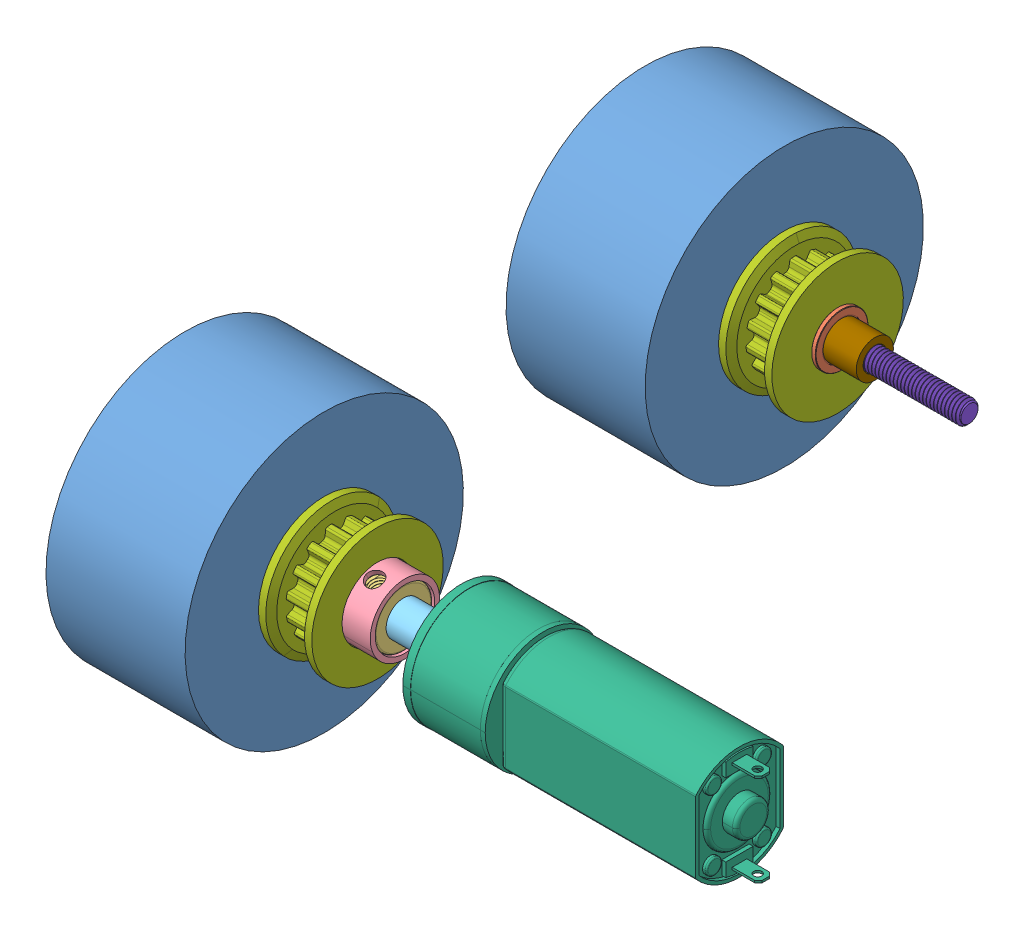
SolidWorks assembly Drive Assembly, configuration Default. Lengths in mm.
Overall size (83.14 53.85 110.21).
14 component instances, 9 part files, 24 mates.
Components (placement in the parent):
- Wheel-2: Wheel [Default] at (-39.5685 0 -62.992) x (0 0.997721 -0.06747) z (1 0 0) size (38.1 38.1 19.05)
- 3 mm Flanged Bearing 57155K538-3: 3 mm Flanged Bearing 57155K538 [57155K538] at (-23.3935 0 -62.992) x (0 0.996899 0.078694) z (-1 0 0) size (7.2 7.2 2.5)
- 3 mm Flanged Bearing 57155K538-4: 3 mm Flanged Bearing 57155K538 [57155K538] at (-48.4435 0 -62.992) x (0 0.017248 0.999851) z (1 0 0) size (7.2 7.2 2.5)
- Lite_Hub-1: Lite_Hub [Default] at (-34.4741 1.8479 0.5975) x (-1 0 0) z (0 -0.369003 0.929428) size (25.61 15 9.51)
  - Lite_Hub.IGS-1: Lite_Hub.IGS [Default] at origin size (25.61 15 9.51)
    - Lite hubs.IGS-1: Lite hubs.IGS [Default] at (-15.2866 1.938 0.1266) size (25.41 15 8.06)
    - Hub Sleeve R2.IGS-1: Hub Sleeve R2.IGS [Default] at (-10.6565 1.938 0.1266) x (0 0 1) z (-1 0 0) size (9.51 9.51 4.84)
- Drive Gear Spacer-1: Drive Gear Spacer [Default] at (-15.2188 0 0) x (0 -0.973557 0.228446) z (1 0 0) size (4.76 4.76 7.94)
- FingerTech_Silver_Spark_223350-2: FingerTech_Silver_Spark_223350 [Default] at origin size (79.67 16.08 16.08)
- Drive Pulley-1: Drive Pulley [Default] at (-26.3935 0 0) x (-1 0 0) z (0 -0.683814 0.729656) size (26.35 18 18)
- Wheel-3: Wheel [Default] at (-39.5685 0 0) x (0 -0.683814 0.729656) z (-1 0 0) size (38.1 38.1 19.05)
- Drive Pulley-2: Drive Pulley [Front] at (-26.3935 0 -62.992) x (-1 0 0) z (0 -0.997721 0.06747) size (26.35 18 18)
- M3 45 mm Long Socket Head 91290A079-1: M3 45 mm Long Socket Head 91290A079 [91290A079] at (-28.6935 0 -62.992) x (0 0 1) z (-1 0 0) size (5.5 5.5 48.33)
- Bearing Spacer-1: Bearing Spacer [Default] at (-19.9205 0 -62.992) x (0 0 1) z (-1 0 0) size (5.08 5.08 4.54)
Mates (geometry in assembly coordinates):
- Coincident39: coincident: line of Lite_Hub-1 through (-44.5885 0 0) axis (1 0 0)
- Concentric16: concentric anti-aligned: cylinder of Drive Gear Spacer-1 through (-11.25 0 0) axis (-1 0 0) radius 1.5; cylinder of FingerTech_Silver_Spark_223350-2 through (-49.26 0 0) axis (1 0 0) radius 1.49
- Coincident49: coincident anti-aligned: plane of Drive Gear Spacer-1 through (-11.25 0 0) normal (1 0 0); plane of FingerTech_Silver_Spark_223350-2 through (-11.25 0 0) normal (-1 0 0)
- Concentric17: concentric aligned: line of Lite_Hub-1 through (-44.5885 0 0) axis (1 0 0); cylinder of FingerTech_Silver_Spark_223350-2 through (-49.26 0 0) axis (1 0 0) radius 1.49
- Tangent3: tangent: plane of assembly; face of Lite_Hub-1/Lite_Hub.IGS-1/Lite hubs.IGS-1; plane of Drive Gear Spacer-1 through (-19.1875 0 0) normal (-1 0 0)
- Concentric18: concentric aligned: line of Lite_Hub-1 through (-44.5885 0 0) axis (1 0 0); cylinder of Drive Pulley-1 through (-44.5875 0 0) axis (1 0 0) radius 2.1574
- Tangent4: tangent: plane of assembly; face of Lite_Hub-1/Lite_Hub.IGS-1/Lite hubs.IGS-1; plane of Drive Pulley-1 through (-24.0135 0 0) normal (1 0 0)
- Coincident52: coincident anti-aligned: plane of Drive Pulley-1 through (-30.0435 0 0) normal (-1 0 0); plane of Wheel-3 through (-30.0435 0 0) normal (1 0 0)
- Concentric20: concentric anti-aligned: cylinder of Drive Pulley-1 through (-4.0877 0 0) axis (-1 0 0) radius 9; cylinder of Wheel-3 through (-49.0935 0 0) axis (1 0 0) radius 19.05
- Coincident53: coincident anti-aligned: plane of Drive Pulley-1 through (-26.3935 0 0) normal (0 -0.729656 -0.683814); plane of Wheel-3 through (-39.5685 0 0) normal (0 0.729656 0.683814)
- Concentric21: concentric aligned: cylinder of Wheel-2 through (-30.0435 0 -62.992) axis (-1 0 0) radius 19.05; cylinder of Drive Pulley-2 through (-4.0877 0 -62.992) axis (-1 0 0) radius 9
- Coincident54: coincident anti-aligned: plane of Wheel-2 through (-30.0435 0 -62.992) normal (1 0 0); plane of Drive Pulley-2 through (-30.0435 0 -62.992) normal (-1 0 0)
- Coincident55: coincident anti-aligned: plane of Wheel-2 through (-39.5685 0 -62.992) normal (0 0.06747 0.997721); plane of Drive Pulley-2 through (-26.3935 0 -62.992) normal (0 -0.06747 -0.997721)
- Coincident56: coincident: line of Drive Pulley-2 through (-20.3988 0 -62.992) axis (-1 0 0)
- Coincident58: coincident aligned: plane of Drive Pulley-1 through (-22.7435 0 0) normal (1 0 0); plane of Drive Pulley-2 through (-22.7435 0 -62.992) normal (1 0 0)
- Concentric23: concentric aligned: cylinder of 3 mm Flanged Bearing 57155K538-3 through (-23.3935 0 -62.992) axis (-1 0 0) radius 3; line of Drive Pulley-2 through (-20.3988 0 -62.992) axis (-1 0 0)
- Coincident59: coincident anti-aligned: plane of 3 mm Flanged Bearing 57155K538-3 through (-22.7435 0.2833 -66.5808) normal (-1 0 0); plane of Drive Pulley-2 through (-22.7435 0 -62.992) normal (1 0 0)
- Concentric24: concentric anti-aligned: cylinder of 3 mm Flanged Bearing 57155K538-4 through (-48.4435 0 -62.992) axis (1 0 0) radius 3; line of Drive Pulley-2 through (-20.3988 0 -62.992) axis (-1 0 0)
- Coincident60: coincident anti-aligned: plane of 3 mm Flanged Bearing 57155K538-4 through (-49.0935 -3.5995 -62.9299) normal (1 0 0); plane of Drive Pulley-2 through (-49.0935 -2.8736 -70.168) normal (-1 0 0)
- Distance1: distance = 62.992 mm: cylinder of Wheel-2 through (-30.0435 0 -62.992) axis (-1 0 0) radius 19.05; cylinder of Wheel-3 through (-49.0935 0 0) axis (1 0 0) radius 19.05
- Concentric27: concentric anti-aligned: cylinder of 3 mm Flanged Bearing 57155K538-3 through (-23.3935 0 -62.992) axis (-1 0 0) radius 1.5; cylinder of M3 45 mm Long Socket Head 91290A079-1 through (-4.6935 0 -62.992) axis (1 0 0) radius 1.5541
- Coincident63: coincident anti-aligned: plane of 3 mm Flanged Bearing 57155K538-4 through (-49.6935 -1.9872 -62.9577) normal (-1 0 0); plane of M3 45 mm Long Socket Head 91290A079-1 through (-49.6935 2.6 -62.992) normal (1 0 0)
- Concentric28: concentric anti-aligned: cylinder of 3 mm Flanged Bearing 57155K538-3 through (-23.3935 0 -62.992) axis (-1 0 0) radius 1.5; cylinder of Bearing Spacer-1 through (-22.1923 0 -62.992) axis (1 0 0) radius 1.6
- Coincident64: coincident anti-aligned: plane of 3 mm Flanged Bearing 57155K538-3 through (-22.1923 0.1701 -65.1473) normal (1 0 0); plane of Bearing Spacer-1 through (-22.1923 0 -62.992) normal (-1 0 0)
